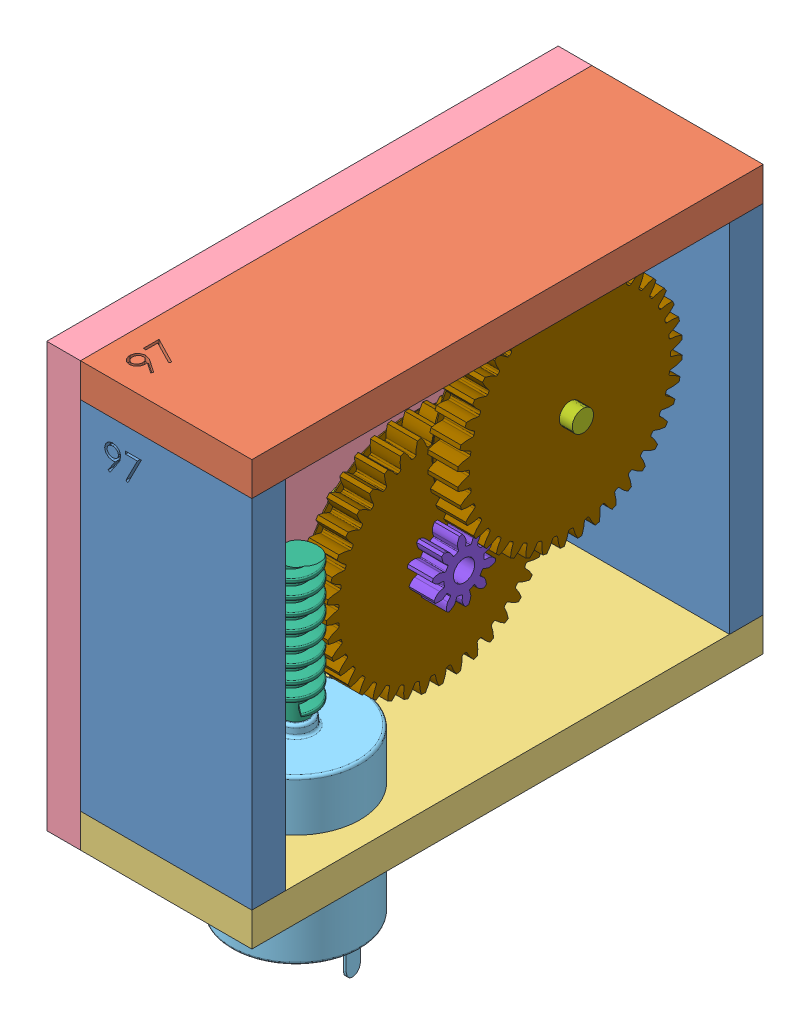
SolidWorks assembly 97_GearBoxAcrylic, configuration Default. Lengths in mm.
Overall size (49.7 99.91 95.51).
12 component instances, 9 part files, 0 mates.
Components (placement in the parent):
- 97_SidePlate_AC_N2-1: 97_SidePlate_AC_N2 [Default] at (12.369 -35.4562 -89.426) size (32 66.56 6.3)
- 97_SidePlate_AC_N2-2: 97_SidePlate_AC_N2 [Default] at (12.369 -35.4562 -0.2179) size (32 66.56 6.3)
- 97_TopPlate_AC_N1-1: 97_TopPlate_AC_N1 [Default] at (-25.631 34.1161 -46.7179) x (0 0 -1) z (0 1 0) size (95.51 32 6.3)
- 97_BottomPlate_AC_N1-1: 97_BottomPlate_AC_N1 [Default] at (12.369 -38.747 -46.7179) x (0 0 1) z (0 1 0) size (95.51 32 6.3)
- 97_BackPlate_AC_N1-1-1: 97_BackPlate_AC_N1-1 [Default] at (-28.931 0 -77.0439) x (0 0 -1) z (1 0 0) size (95.51 79.16 6.3)
- DCMotor1 - NOPRINT-1: DCMotor1 - NOPRINT [Default] at (-7.131 -53.496 -18.6179) x (0.994033 0 -0.109084) z (0 1 0) size (24 24 48.5)
- Worm Gear - NOPRINT-1: Worm Gear - NOPRINT [Default] at (-7.131 -20.996 -18.6179) x (-0.817926 0 -0.575323) z (0 1 0) size (9.28 9.15 25.25)
- Shaft - NOPRINT-1: Shaft - NOPRINT [Default] at (-40.3278 -5.817 -42.0399) x (0 0.942739 -0.333533) z (1 0 0) size (4 4 38)
- Shaft - NOPRINT-2: Shaft - NOPRINT [Default] at (4.4595 10.8716 -60.6542) x (0 0.14972 -0.988728) z (-1 0 0) size (4 4 38)
- 10T - NOPRINT-1: 10T - NOPRINT [Default] at (-4.8656 -5.817 -42.0399) x (0 -0.21694 -0.976185) z (1 0 0) size (12 11.58 6)
- 40T - NOPRINT-1: 40T - NOPRINT [Default] at (-9.4018 -5.817 -42.0399) x (0 0.173701 -0.984799) z (1 0 0) size (42 42 5.85)
- 40T - NOPRINT-2: 40T - NOPRINT [Default] at (-3.5518 10.8716 -60.6542) x (0 0.068717 0.997636) z (1 0 0) size (42 42 5.85)
